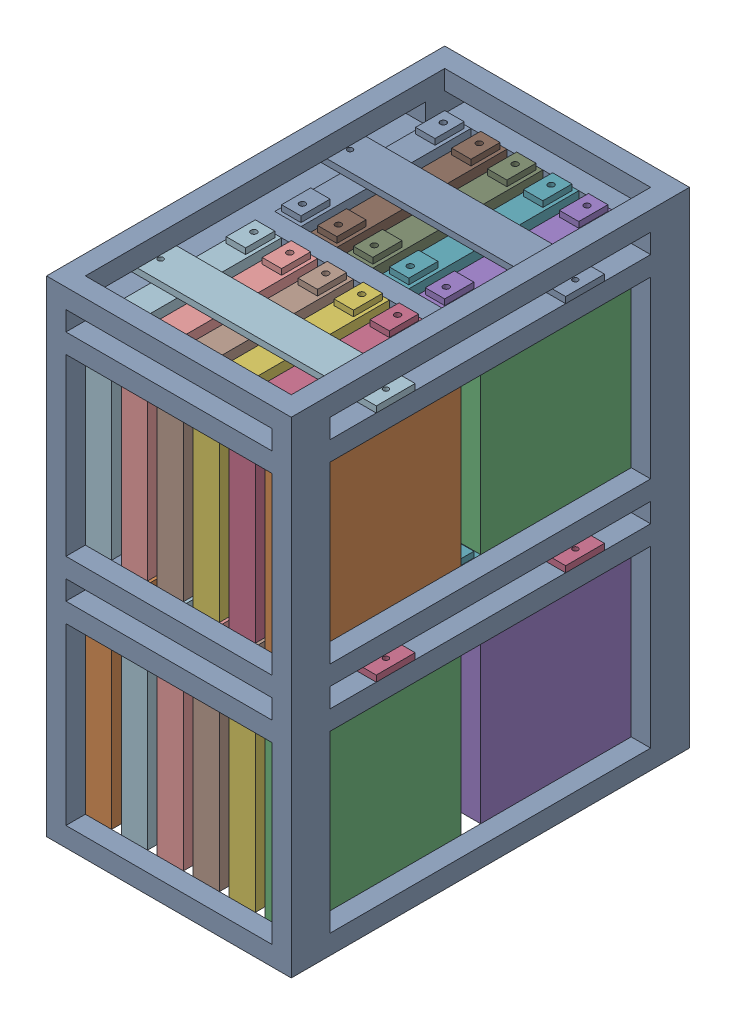
SolidWorks assembly pack assembly prototype, configuration Default. Lengths in mm.
Overall size (252 500 410).
49 component instances, 4 part files, 8 mates.
Components (placement in the parent):
- frame prototype-1: frame prototype [Default] at origin size (252 500 410)
- bracket prototype-1: bracket prototype [Default] at (74 0 97.5) size (10 25 40)
- battery-14: battery [Default] at (92.5 0 97.5) size (27 206 175)
- retaining bar prototype-1: retaining bar prototype [Default] at (0 200 97.5) x (0 0 1) z (-1 0 0) size (40 6.35 252)
- battery-15: battery [Default] at (92.5 0 -97.5) size (27 206 175)
- battery-16: battery [Default] at (55.5 0 97.5) size (27 206 175)
- battery-17: battery [Default] at (55.5 0 -97.5) size (27 206 175)
- battery-18: battery [Default] at (18.5 0 97.5) size (27 206 175)
- battery-19: battery [Default] at (18.5 0 -97.5) size (27 206 175)
- battery-20: battery [Default] at (-18.5 0 97.5) size (27 206 175)
- battery-21: battery [Default] at (-18.5 0 -97.5) size (27 206 175)
- battery-22: battery [Default] at (-55.5 0 97.5) size (27 206 175)
- battery-23: battery [Default] at (-55.5 0 -97.5) size (27 206 175)
- battery-24: battery [Default] at (-92.5 0 97.5) size (27 206 175)
- battery-25: battery [Default] at (-92.5 0 -97.5) size (27 206 175)
- retaining bar prototype-2: retaining bar prototype [Default] at (0 200 -97.5) x (0 0 1) z (-1 0 0) size (40 6.35 252)
- bracket prototype-2: bracket prototype [Default] at (74 0 -97.5) size (10 25 40)
- bracket prototype-3: bracket prototype [Default] at (37 0 97.5) size (10 25 40)
- bracket prototype-4: bracket prototype [Default] at (37 0 -97.5) size (10 25 40)
- bracket prototype-5: bracket prototype [Default] at (0 0 97.5) size (10 25 40)
- bracket prototype-6: bracket prototype [Default] at (0 0 -97.5) size (10 25 40)
- bracket prototype-7: bracket prototype [Default] at (-37 0 97.5) size (10 25 40)
- bracket prototype-8: bracket prototype [Default] at (-37 0 -97.5) size (10 25 40)
- bracket prototype-9: bracket prototype [Default] at (-74 0 97.5) size (10 25 40)
- bracket prototype-10: bracket prototype [Default] at (-74 0 -97.5) size (10 25 40)
- bracket prototype-11: bracket prototype [Default] at (74 240 97.5) size (10 25 40)
- bracket prototype-12: bracket prototype [Default] at (74 240 -97.5) size (10 25 40)
- bracket prototype-13: bracket prototype [Default] at (37 240 97.5) size (10 25 40)
- bracket prototype-14: bracket prototype [Default] at (37 240 -97.5) size (10 25 40)
- bracket prototype-15: bracket prototype [Default] at (0 240 97.5) size (10 25 40)
- bracket prototype-16: bracket prototype [Default] at (0 240 -97.5) size (10 25 40)
- bracket prototype-17: bracket prototype [Default] at (-37 240 97.5) size (10 25 40)
- bracket prototype-18: bracket prototype [Default] at (-37 240 -97.5) size (10 25 40)
- bracket prototype-19: bracket prototype [Default] at (-74 240 97.5) size (10 25 40)
- bracket prototype-20: bracket prototype [Default] at (-74 240 -97.5) size (10 25 40)
- retaining bar prototype-3: retaining bar prototype [Default] at (0 440 97.5) x (0 0 1) z (-1 0 0) size (40 6.35 252)
- retaining bar prototype-4: retaining bar prototype [Default] at (0 440 -97.5) x (0 0 1) z (-1 0 0) size (40 6.35 252)
- battery-26: battery [Default] at (92.5 240 97.5) size (27 206 175)
- battery-27: battery [Default] at (92.5 240 -97.5) size (27 206 175)
- battery-28: battery [Default] at (55.5 240 97.5) size (27 206 175)
- battery-29: battery [Default] at (55.5 240 -97.5) size (27 206 175)
- battery-30: battery [Default] at (18.5 240 97.5) size (27 206 175)
- battery-31: battery [Default] at (18.5 240 -97.5) size (27 206 175)
- battery-32: battery [Default] at (-18.5 240 97.5) size (27 206 175)
- battery-33: battery [Default] at (-18.5 240 -97.5) size (27 206 175)
- battery-34: battery [Default] at (-55.5 240 97.5) size (27 206 175)
- battery-35: battery [Default] at (-55.5 240 -97.5) size (27 206 175)
- battery-36: battery [Default] at (-92.5 240 97.5) size (27 206 175)
- battery-37: battery [Default] at (-92.5 240 -97.5) size (27 206 175)
Mates (geometry in assembly coordinates):
- Coincident7: coincident aligned: circle of frame prototype-1; circle of retaining bar prototype-1
- Parallel1: parallel aligned: plane of frame prototype-1 through (0 -20 205) normal (0 0 1); plane of retaining bar prototype-1 through (0 206.35 117.5) normal (0 0 1)
- Coincident12: coincident anti-aligned: plane of frame prototype-1 through (-134.2843 0 185) normal (0 0 -1); plane of battery-14 through (79 200 185) normal (0 0 1)
- Coincident13: coincident anti-aligned: plane of frame prototype-1 through (106 -20 0) normal (-1 0 0); plane of battery-14 through (106 200 185) normal (1 0 0)
- Coincident14: coincident anti-aligned: plane of frame prototype-1 through (0 0 0) normal (0 1 0); plane of battery-14 through (92.5 0 97.5) normal (0 -1 0)
- Coincident15: coincident anti-aligned: plane of bracket prototype-1 through (79 1.5875 97.5) normal (1 0 0); plane of battery-14 through (79 200 185) normal (-1 0 0)
- Coincident16: coincident aligned: plane of frame prototype-1 through (-106 -20 117.5) normal (0 0 1); plane of bracket prototype-1 through (74 1.5875 117.5) normal (0 0 1)
- Coincident17: coincident anti-aligned: plane of frame prototype-1 through (0 0 0) normal (0 1 0); plane of bracket prototype-1 through (74 0 97.5) normal (0 -1 0)
